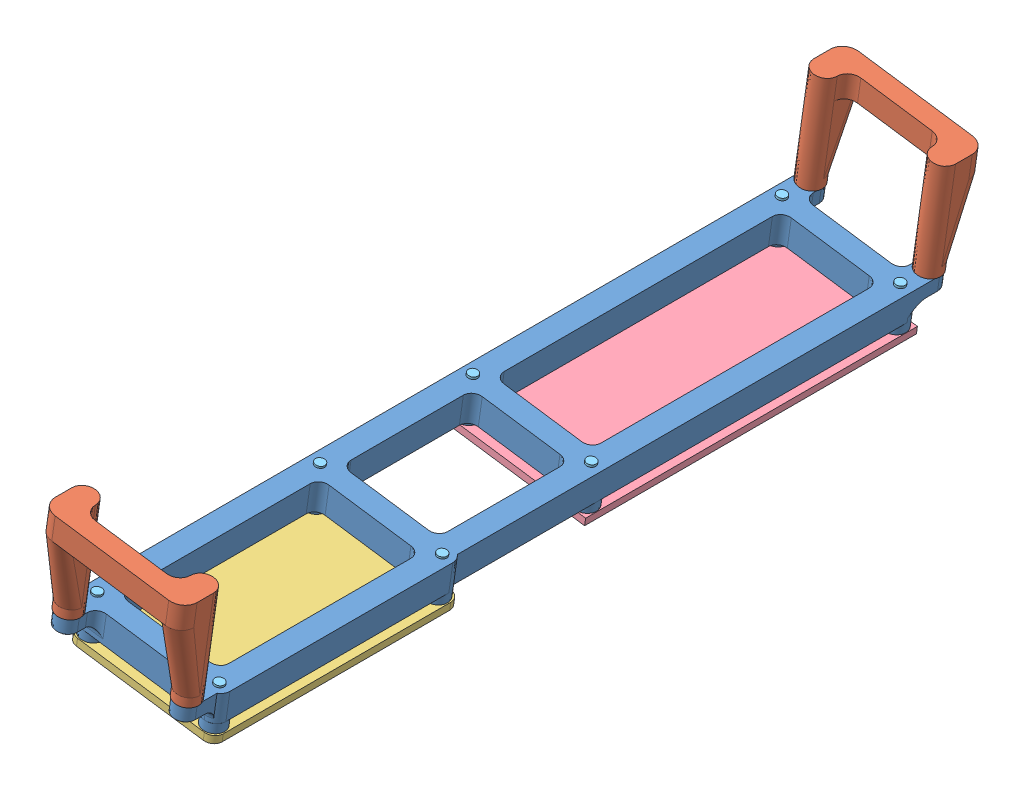
SolidWorks assembly PCBassem, configuration Default. Lengths in mm.
Overall size (39.16 41.45 169.74).
17 component instances, 5 part files, 36 mates.
Components (placement in the parent):
- PcbBaseHolder-1: PcbBaseHolder [По умолчанию] at (-28.7058 -55.8577 -8.1725) size (31.52 12.27 161.11)
- PcbStand-1: PcbStand [По умолчанию] at (-28.7058 -55.8577 -8.1725) size (33.07 26.45 9.11)
- PcbStand-2: PcbStand [По умолчанию] at (96.8197 -73.8219 262.3917) x (-0.95986 0.280479 0) z (0 0 -1) size (33.07 26.45 9.11)
- pcbBU0836A-1: pcbBU0836A [По умолчанию] at (54.8294 77.0169 175.8748) x (0.989914 -0.141669 -0.000692) z (0.141669 0.989914 0) size (31 52 1.6)
- pcbBreadboard-1: pcbBreadboard [По умолчанию] at (54.3102 77.1922 87.4621) x (0.989914 -0.141669 -0.000692) z (0.141669 0.989914 0) size (30 70 1.5)
- M2x10selftapping-1: M2x10selftapping [Default] at (42.7804 85.4085 48.8533) x (0.32347 -0.046293 -0.945105) z (-0.935573 0.133892 -0.326766) size (3.4 11.3 3.4)
- M2x10selftapping-2: M2x10selftapping [Default] at (67.7263 81.8385 48.8533) x (0.121266 -0.017355 -0.992468) z (-0.982458 0.140602 -0.122502) size (3.4 11.3 3.4)
- M2x10selftapping-3: M2x10selftapping [Default] at (42.8794 85.3943 205.3658) x (-0.107806 0.015428 -0.994052) z (-0.984026 0.140826 0.108904) size (3.4 11.3 3.4)
- M2x10selftapping-4: M2x10selftapping [Default] at (67.7263 81.8385 205.3658) x (-0.342536 0.049021 -0.938225) z (-0.928762 0.132917 0.346026) size (3.4 11.3 3.4)
- M2x10selftapping-6: M2x10selftapping [Default] at (41.8149 78.9805 54.8708) x (0.32347 -0.046293 -0.945105) z (-0.935573 0.133892 -0.326766) size (3.4 11.3 3.4)
- M2x10selftapping-7: M2x10selftapping [Default] at (66.7607 75.4104 54.8534) x (0.121266 -0.017355 -0.992468) z (-0.982458 0.140602 -0.122502) size (3.4 11.3 3.4)
- M2x10selftapping-8: M2x10selftapping [Default] at (41.8596 78.9741 120.0708) x (-0.107806 0.015428 -0.994052) z (-0.984026 0.140826 0.108904) size (3.4 11.3 3.4)
- M2x10selftapping-9: M2x10selftapping [Default] at (66.8054 75.404 120.0533) x (-0.342536 0.049021 -0.938225) z (-0.928762 0.132917 0.346026) size (3.4 11.3 3.4)
- M2x10selftapping-10: M2x10selftapping [Default] at (41.9444 78.8609 152.3838) x (-0.554532 0.07936 -0.828369) z (-0.820015 0.117354 0.560182) size (3.4 11.3 3.4)
- M2x10selftapping-12: M2x10selftapping [Default] at (67.6822 75.1775 152.3658) x (-0.720397 0.103097 -0.685856) z (-0.678939 0.097164 0.727737) size (3.4 11.3 3.4)
- M2x10selftapping-14: M2x10selftapping [Default] at (41.9766 78.8563 199.3838) x (-0.832004 0.11907 -0.541842) z (-0.536377 0.076762 0.840481) size (3.4 11.3 3.4)
- M2x10selftapping-16: M2x10selftapping [Default] at (67.7144 75.1729 199.3658) x (-0.896191 0.128256 -0.424726) z (-0.420442 0.06017 0.905322) size (3.4 11.3 3.4)
Mates (geometry in assembly coordinates):
- Concentric2: concentric anti-aligned: cylinder of PcbBaseHolder-1 through (67.7263 81.8385 48.8533) axis (0.141669 0.989914 0) radius 1.15; cylinder of PcbStand-1 through (69.2846 92.7275 48.8533) axis (-0.141669 -0.989914 0) radius 0.85
- Coincident1: coincident anti-aligned: plane of PcbBaseHolder-1 through (-7.0349 95.5682 -8.1725) normal (0.141669 0.989914 0); plane of PcbStand-1 through (68.1513 84.8082 48.8533) normal (-0.141669 -0.989914 0)
- Concentric5: concentric anti-aligned: cylinder of PcbBaseHolder-1 through (42.8794 85.3943 205.3658) axis (0.141669 0.989914 0) radius 1.15; cylinder of PcbStand-2 through (44.4378 96.2834 205.3658) axis (-0.141669 -0.989914 0) radius 0.85
- Coincident2: coincident anti-aligned: plane of PcbBaseHolder-1 through (-7.0349 95.5682 -8.1725) normal (0.141669 0.989914 0); plane of PcbStand-2 through (43.3044 88.3641 205.3658) normal (-0.141669 -0.989914 0)
- Parallel1: parallel aligned: plane of PcbBaseHolder-1 through (-7.0349 95.5682 201.6658) normal (0 0 1); plane of PcbStand-2 through (120.9556 94.8285 211.8658) normal (0 0 1)
- Parallel2: parallel aligned: plane of PcbBaseHolder-1 through (-7.0349 95.5682 52.5533) normal (0 0 -1); plane of PcbStand-1 through (-4.5698 112.7927 42.3533) normal (0 0 -1)
- Coincident3: coincident anti-aligned: plane of PcbBaseHolder-1 through (67.0179 76.8889 120.0533) normal (-0.141669 -0.989914 0); plane of pcbbb-1 through (54.5227 78.6771 87.4621) normal (0.141669 0.989914 0)
- Coincident4: coincident anti-aligned: plane of PcbBaseHolder-1 through (67.9088 76.7614 152.3658) normal (-0.141669 -0.989914 0); plane of pcbusb-1 through (68.4363 76.6859 199.8655) normal (0.141669 0.989914 0)
- Concentric9: concentric aligned: cylinder of PcbBaseHolder-1 through (69.0422 84.6807 152.3658) axis (-0.141669 -0.989914 0) radius 0.8; cylinder of pcbusb-1 through (67.9088 76.7614 152.3658) axis (-0.141669 -0.989914 0) radius 1.25
- Concentric10: concentric aligned: cylinder of PcbBaseHolder-1 through (68.1513 84.8082 120.0533) axis (-0.141669 -0.989914 0) radius 0.8; cylinder of pcbbb-1 through (67.0179 76.8889 120.0533) axis (-0.141669 -0.989914 0) radius 1
- Parallel3: parallel aligned: plane of PcbBaseHolder-1 through (40.8854 88.7103 -8.206) normal (-0.989914 0.141669 0.000692); plane of pcbusb-1 through (39.6959 80.799 151.8856) normal (-0.989914 0.141669 0.000692)
- Parallel4: parallel aligned: plane of PcbBaseHolder-1 through (40.8854 88.7103 -8.206) normal (-0.989914 0.141669 0.000692); plane of pcbbb-1 through (39.6979 80.7987 122.4724) normal (-0.989914 0.141669 0.000692)
- Concentric11: concentric anti-aligned: cylinder of PcbBaseHolder-1 through (42.7804 85.4085 48.8533) axis (0.141669 0.989914 0) radius 1.15; cylinder of M2x10selftapping-1 through (42.7804 85.4085 48.8533) axis (-0.141669 -0.989914 0) radius 1
- Coincident5: coincident anti-aligned: plane of PcbBaseHolder-1 through (42.7804 85.4085 54.8533) normal (-0.141669 -0.989914 0); plane of M2x10selftapping-1 through (42.457 85.4548 49.7984) normal (0.141669 0.989914 0)
- Concentric12: concentric anti-aligned: cylinder of PcbBaseHolder-1 through (67.7263 81.8385 48.8533) axis (0.141669 0.989914 0) radius 1.15; cylinder of M2x10selftapping-2 through (67.7263 81.8385 48.8533) axis (-0.141669 -0.989914 0) radius 1
- Coincident6: coincident anti-aligned: plane of PcbBaseHolder-1 through (42.7804 85.4085 54.8533) normal (-0.141669 -0.989914 0); plane of M2x10selftapping-2 through (67.605 81.8558 49.8458) normal (0.141669 0.989914 0)
- Coincident7: coincident anti-aligned: plane of PcbBaseHolder-1 through (42.7804 85.4085 54.8533) normal (-0.141669 -0.989914 0); plane of M2x10selftapping-3 through (42.9872 85.3789 206.3599) normal (0.141669 0.989914 0)
- Concentric13: concentric anti-aligned: cylinder of PcbBaseHolder-1 through (42.8794 85.3943 205.3658) axis (0.141669 0.989914 0) radius 1.15; cylinder of M2x10selftapping-3 through (42.8794 85.3943 205.3658) axis (-0.141669 -0.989914 0) radius 1
- Coincident8: coincident anti-aligned: plane of PcbBaseHolder-1 through (42.7804 85.4085 54.8533) normal (-0.141669 -0.989914 0); plane of M2x10selftapping-4 through (68.0688 81.7894 206.3041) normal (0.141669 0.989914 0)
- Concentric14: concentric anti-aligned: cylinder of PcbBaseHolder-1 through (67.7263 81.8385 205.3658) axis (0.141669 0.989914 0) radius 1.15; cylinder of M2x10selftapping-4 through (67.7263 81.8385 205.3658) axis (-0.141669 -0.989914 0) radius 1
- Concentric15: concentric aligned: cylinder of pcbbb-1 through (42.0274 80.4653 54.8708) axis (-0.141669 -0.989914 0) radius 1; cylinder of M2x10selftapping-6 through (41.8149 78.9805 54.8708) axis (-0.141669 -0.989914 0) radius 1
- Coincident10: coincident anti-aligned: plane of pcbbb-1 through (54.3102 77.1922 87.4621) normal (-0.141669 -0.989914 0); plane of M2x10selftapping-6 through (41.4914 79.0267 55.8159) normal (0.141669 0.989914 0)
- Concentric16: concentric aligned: cylinder of pcbbb-1 through (66.9733 76.8953 54.8534) axis (-0.141669 -0.989914 0) radius 1; cylinder of M2x10selftapping-7 through (66.7607 75.4104 54.8534) axis (-0.141669 -0.989914 0) radius 1
- Coincident11: coincident anti-aligned: plane of pcbbb-1 through (54.3102 77.1922 87.4621) normal (-0.141669 -0.989914 0); plane of M2x10selftapping-7 through (66.6395 75.4278 55.8458) normal (0.141669 0.989914 0)
- Coincident12: coincident anti-aligned: plane of pcbbb-1 through (54.3102 77.1922 87.4621) normal (-0.141669 -0.989914 0); plane of M2x10selftapping-8 through (41.9674 78.9586 121.0648) normal (0.141669 0.989914 0)
- Concentric17: concentric aligned: cylinder of pcbbb-1 through (42.0721 80.4589 120.0708) axis (-0.141669 -0.989914 0) radius 1; cylinder of M2x10selftapping-8 through (41.8596 78.9741 120.0708) axis (-0.141669 -0.989914 0) radius 1
- Coincident13: coincident anti-aligned: plane of pcbbb-1 through (54.3102 77.1922 87.4621) normal (-0.141669 -0.989914 0); plane of M2x10selftapping-9 through (67.1479 75.355 120.9916) normal (0.141669 0.989914 0)
- Concentric18: concentric aligned: cylinder of pcbbb-1 through (67.0179 76.8889 120.0533) axis (-0.141669 -0.989914 0) radius 1; cylinder of M2x10selftapping-9 through (66.8054 75.404 120.0533) axis (-0.141669 -0.989914 0) radius 1
- Concentric19: concentric aligned: cylinder of pcbusb-1 through (42.1711 80.4448 152.3838) axis (-0.141669 -0.989914 0) radius 1.25; cylinder of M2x10selftapping-10 through (41.9444 78.8609 152.3838) axis (-0.141669 -0.989914 0) radius 1
- Coincident16: coincident anti-aligned: plane of pcbusb-1 through (68.2097 75.102 199.8655) normal (-0.141669 -0.989914 0); plane of M2x10selftapping-10 through (42.4989 78.7815 153.2122) normal (0.141669 0.989914 0)
- Concentric20: concentric aligned: cylinder of pcbusb-1 through (67.9088 76.7614 152.3658) axis (-0.141669 -0.989914 0) radius 1.25; cylinder of M2x10selftapping-12 through (67.6822 75.1775 152.3658) axis (-0.141669 -0.989914 0) radius 1
- Coincident17: coincident anti-aligned: plane of pcbusb-1 through (68.2097 75.102 199.8655) normal (-0.141669 -0.989914 0); plane of M2x10selftapping-12 through (68.4026 75.0744 153.0517) normal (0.141669 0.989914 0)
- Concentric21: concentric aligned: cylinder of pcbusb-1 through (42.2033 80.4402 199.3838) axis (-0.141669 -0.989914 0) radius 1.25; cylinder of M2x10selftapping-14 through (41.9766 78.8563 199.3838) axis (-0.141669 -0.989914 0) radius 1
- Coincident18: coincident anti-aligned: plane of pcbusb-1 through (68.2097 75.102 199.8655) normal (-0.141669 -0.989914 0); plane of M2x10selftapping-14 through (42.8086 78.7372 199.9257) normal (0.141669 0.989914 0)
- Concentric22: concentric aligned: cylinder of pcbusb-1 through (67.941 76.7568 199.3658) axis (-0.141669 -0.989914 0) radius 1.25; cylinder of M2x10selftapping-16 through (67.7144 75.1729 199.3658) axis (-0.141669 -0.989914 0) radius 1
- Coincident19: coincident anti-aligned: plane of pcbusb-1 through (68.2097 75.102 199.8655) normal (-0.141669 -0.989914 0); plane of M2x10selftapping-16 through (68.6106 75.0447 199.7906) normal (0.141669 0.989914 0)
